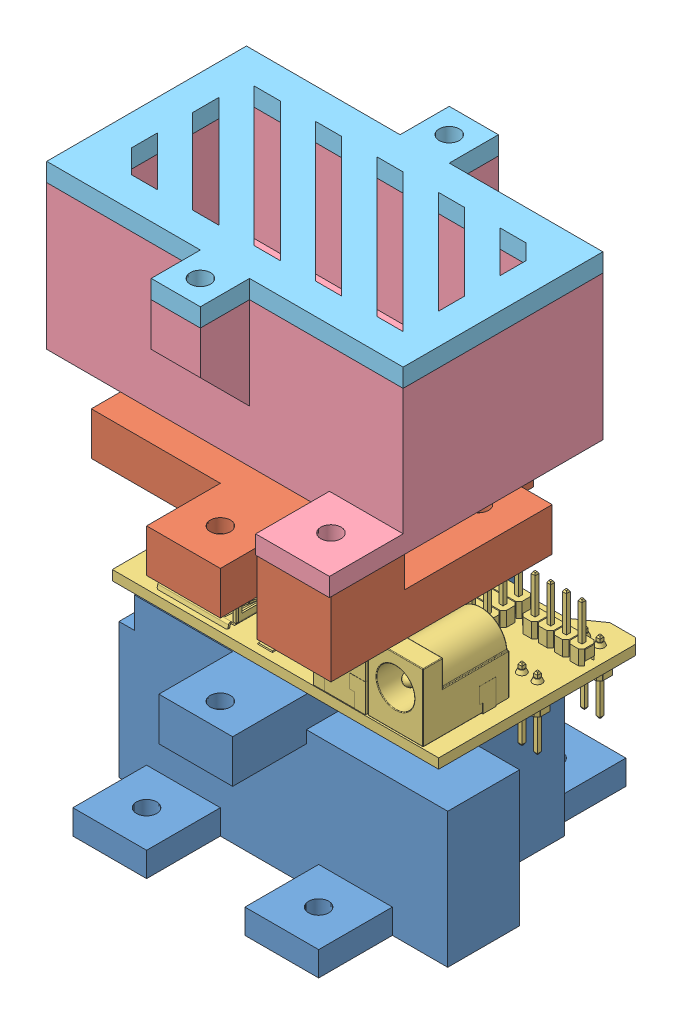
SolidWorks assembly Power Supply, configuration Default. Lengths in mm.
Overall size (63 83.22 56.25).
5 component instances, 5 part files, 8 mates.
Components (placement in the parent):
- Power supply mount base-1: Power supply mount base [Default] at (-24.8975 -6.4272 52.1775) x (-1 0 0) z (0 0 1) size (53.5 27 52)
- Power supply mount top-1: Power supply mount top [Default] at (-36.8975 11.2907 54.1775) size (51 12 56)
- Modelo3D_AR0484.step-1: Modelo3D_AR0484.step [Default] at (-28.6088 -56.1831 36.3244) x (1 0 0) z (0 1 0) size (53.1 33.04 23.89)
- 9V_Battery_Bath-1: 9V_Battery_Bath [Default] at (-61.8975 23.2907 54.4275) x (0 0 -1) z (1 0 0) size (55.5 23.5 58)
- 9V_Battery_Bath_Lid-1: 9V_Battery_Bath_Lid [Default] at (-6.8975 46.7907 54.4275) x (0 0 -1) z (1 0 0) size (48.5 3 58)
Mates (geometry in assembly coordinates):
- Coincident2: coincident anti-aligned: plane of Power supply mount base-1 through (-24.8975 -6.4272 52.1775) normal (0 1 0); plane of Modelo3D_AR0484.step-1 through (-30.1045 -6.4272 35.5002) normal (0 -1 0)
- Concentric2: concentric aligned: cylinder of Power supply mount base-1 through (-30.8975 -6.4272 60.1775) axis (0 -1 0) radius 1.65; cylinder of Power supply mount top-1 through (-30.8975 18.2907 60.1775) axis (0 -1 0) radius 1.65
- Parallel1: parallel aligned: plane of Power supply mount base-1 through (-24.8975 -11.4272 52.1775) normal (0 0 1); plane of Power supply mount top-1 through (-36.8975 11.2907 54.1775) normal (0 0 1)
- Coincident3: coincident anti-aligned: plane of Power supply mount top-1 through (-36.8975 23.2907 54.1775) normal (0 1 0); plane of 9V_Battery_Bath-1 through (-9.8975 23.2907 54.4275) normal (0 -1 0)
- Concentric3: concentric anti-aligned: cylinder of Power supply mount top-1 through (-12.8975 11.2907 60.1775) axis (0 1 0) radius 1.65; cylinder of 9V_Battery_Bath-1 through (-12.8975 26.2907 60.1775) axis (0 -1 0) radius 1.65
- Concentric4: concentric anti-aligned: cylinder of Power supply mount top-1 through (-47.8975 11.2907 16.1775) axis (0 1 0) radius 1.65; cylinder of 9V_Battery_Bath-1 through (-47.8975 26.2907 16.1775) axis (0 -1 0) radius 1.65
- Coincident4: coincident aligned: circle of 9V_Battery_Bath-1; circle of 9V_Battery_Bath_Lid-1
- Coincident5: coincident aligned: circle of 9V_Battery_Bath-1; circle of 9V_Battery_Bath_Lid-1
